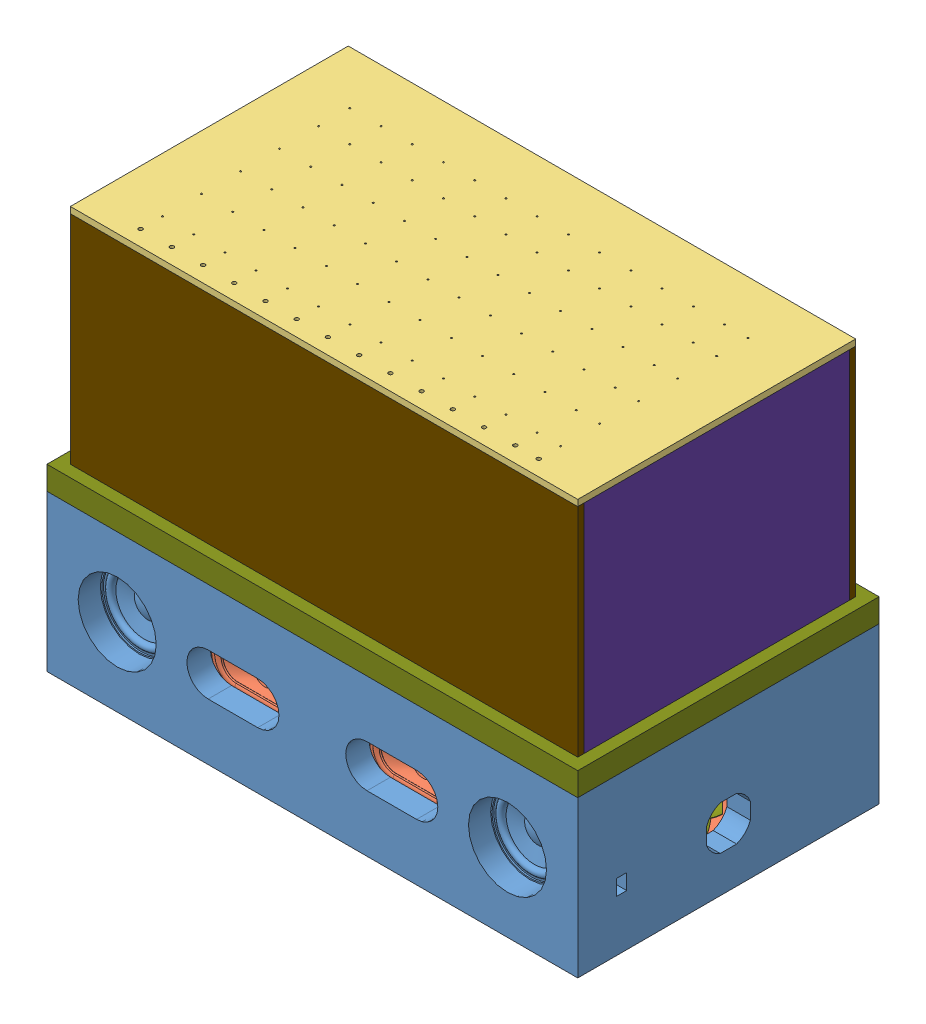
SolidWorks assembly Assem, configuration Default. Lengths in mm.
Overall size (680 515.98 386).
80 component instances, 21 part files, 41 mates.
Components (placement in the parent):
- wooden-base-1: wooden-base [Default] at (295.2164 -47.125 168.8479) size (680 200 386)
- CPU fan-1: CPU fan [Default] at (242.982 19.8629 -67.9288) x (0 -1 0) z (0 0 1) size (86 25 86)
  - Body-1: Body [Default] at (21.396 39.7345 75.157) size (86 25 86)
  - instrument ball bearing_68_am_AFBMA 12.1.4.1 - 0030-8 - Full,DE,NC,Full_68-1: instrument ball bearing_68_am_AFBMA 12.1.4.1 - 0030-8 - Full,DE,NC,Full_68 [Default] at (21.396 39.7345 75.157) x (0 -1 0) z (0 0 1) size (3.01 8 8)
  - Armature-1: Armature [Default] at (-9.8078 18.0489 67.4398) x (0.619703 0 -0.784836) z (0.784836 0 0.619703) size (38.16 6 38.16)
    - Core sub assy-1: Core sub assy [Default] at (-9.1559 6.3072 21.9798) x (0.707107 0 -0.707107) z (0.707107 0 0.707107) size (26.98 5 26.98)
    - Coil-1: Coil [Default] at (13.1895 20.6856 34.4798) x (0.999848 0 0.017452) z (-0.017452 0 0.999848) size (5 6 0.5)
    - Coil-2: Coil [Default] at (13.1807 20.6856 34.9797) x (0.999848 0 0.017452) z (-0.017452 0 0.999848) size (5 6 0.5)
    - Coil-3: Coil [Default] at (13.172 20.6856 35.4797) x (0.999848 0 0.017452) z (-0.017452 0 0.999848) size (5 6 0.5)
    - Coil-4: Coil [Default] at (13.1633 20.6856 35.9796) x (0.999848 0 0.017452) z (-0.017452 0 0.999848) size (5 6 0.5)
    - Coil-5: Coil [Default] at (13.1546 20.6856 36.4795) x (0.999848 0 0.017452) z (-0.017452 0 0.999848) size (5 6 0.5)
    - Coil-6: Coil [Default] at (13.1458 20.6856 36.9794) x (0.999848 0 0.017452) z (-0.017452 0 0.999848) size (5 6 0.5)
    - Coil-7: Coil [Default] at (13.1371 20.6856 37.4794) x (0.999848 0 0.017452) z (-0.017452 0 0.999848) size (5 6 0.5)
    - Coil-8: Coil [Default] at (13.1284 20.6856 37.9793) x (0.999848 0 0.017452) z (-0.017452 0 0.999848) size (5 6 0.5)
    - Coil-9: Coil [Default] at (13.1197 20.6856 38.4792) x (0.999848 0 0.017452) z (-0.017452 0 0.999848) size (5 6 0.5)
    - Coil-10: Coil [Default] at (13.1109 20.6856 38.9791) x (0.999848 0 0.017452) z (-0.017452 0 0.999848) size (5 6 0.5)
    - Coil-11: Coil [Default] at (13.1022 20.6856 39.4791) x (0.999848 0 0.017452) z (-0.017452 0 0.999848) size (5 6 0.5)
    - Coil-12: Coil [Default] at (13.0935 20.6856 39.979) x (0.999848 0 0.017452) z (-0.017452 0 0.999848) size (5 6 0.5)
    - Coil-13: Coil [Default] at (18.488 20.6856 29.3631) x (0.017452 0 -0.999848) z (0.999848 0 0.017452) size (5 6 0.5)
    - Coil-14: Coil [Default] at (13.3713 20.6856 24.0646) x (-0.999848 0 -0.017452) z (0.017452 0 -0.999848) size (5 6 0.5)
    - Coil-15: Coil [Default] at (8.0727 20.6856 29.1813) x (-0.017452 0 0.999848) z (-0.999848 0 -0.017452) size (5 6 0.5)
    - Coil-16: Coil [Default] at (18.9879 20.6856 29.3718) x (0.017452 0 -0.999848) z (0.999848 0 0.017452) size (5 6 0.5)
    - Coil-17: Coil [Default] at (13.38 20.6856 23.5647) x (-0.999848 0 -0.017452) z (0.017452 0 -0.999848) size (5 6 0.5)
    - Coil-18: Coil [Default] at (7.5728 20.6856 29.1726) x (-0.017452 0 0.999848) z (-0.999848 0 -0.017452) size (5 6 0.5)
    - Coil-19: Coil [Default] at (19.4878 20.6856 29.3805) x (0.017452 0 -0.999848) z (0.999848 0 0.017452) size (5 6 0.5)
    - Coil-20: Coil [Default] at (13.3887 20.6856 23.0647) x (-0.999848 0 -0.017452) z (0.017452 0 -0.999848) size (5 6 0.5)
    - Coil-21: Coil [Default] at (7.0729 20.6856 29.1638) x (-0.017452 0 0.999848) z (-0.999848 0 -0.017452) size (5 6 0.5)
    - Coil-22: Coil [Default] at (19.9877 20.6856 29.3893) x (0.017452 0 -0.999848) z (0.999848 0 0.017452) size (5 6 0.5)
    - Coil-23: Coil [Default] at (13.3974 20.6856 22.5648) x (-0.999848 0 -0.017452) z (0.017452 0 -0.999848) size (5 6 0.5)
    - Coil-24: Coil [Default] at (6.573 20.6856 29.1551) x (-0.017452 0 0.999848) z (-0.999848 0 -0.017452) size (5 6 0.5)
    - Coil-25: Coil [Default] at (20.4877 20.6856 29.398) x (0.017452 0 -0.999848) z (0.999848 0 0.017452) size (5 6 0.5)
    - Coil-26: Coil [Default] at (13.4062 20.6856 22.0649) x (-0.999848 0 -0.017452) z (0.017452 0 -0.999848) size (5 6 0.5)
    - Coil-27: Coil [Default] at (6.073 20.6856 29.1464) x (-0.017452 0 0.999848) z (-0.999848 0 -0.017452) size (5 6 0.5)
    - Coil-28: Coil [Default] at (20.9876 20.6856 29.4067) x (0.017452 0 -0.999848) z (0.999848 0 0.017452) size (5 6 0.5)
    - Coil-29: Coil [Default] at (13.4149 20.6856 21.565) x (-0.999848 0 -0.017452) z (0.017452 0 -0.999848) size (5 6 0.5)
    - Coil-30: Coil [Default] at (5.5731 20.6856 29.1377) x (-0.017452 0 0.999848) z (-0.999848 0 -0.017452) size (5 6 0.5)
    - Coil-31: Coil [Default] at (21.4875 20.6856 29.4155) x (0.017452 0 -0.999848) z (0.999848 0 0.017452) size (5 6 0.5)
    - Coil-32: Coil [Default] at (13.4236 20.6856 21.065) x (-0.999848 0 -0.017452) z (0.017452 0 -0.999848) size (5 6 0.5)
    - Coil-33: Coil [Default] at (5.0732 20.6856 29.1289) x (-0.017452 0 0.999848) z (-0.999848 0 -0.017452) size (5 6 0.5)
    - Coil-34: Coil [Default] at (21.9874 20.6856 29.4242) x (0.017452 0 -0.999848) z (0.999848 0 0.017452) size (5 6 0.5)
    - Coil-35: Coil [Default] at (13.4323 20.6856 20.5651) x (-0.999848 0 -0.017452) z (0.017452 0 -0.999848) size (5 6 0.5)
    - Coil-36: Coil [Default] at (4.5733 20.6856 29.1202) x (-0.017452 0 0.999848) z (-0.999848 0 -0.017452) size (5 6 0.5)
    - Coil-37: Coil [Default] at (22.4874 20.6856 29.4329) x (0.017452 0 -0.999848) z (0.999848 0 0.017452) size (5 6 0.5)
    - Coil-38: Coil [Default] at (13.4411 20.6856 20.0652) x (-0.999848 0 -0.017452) z (0.017452 0 -0.999848) size (5 6 0.5)
    - Coil-39: Coil [Default] at (4.0734 20.6856 29.1115) x (-0.017452 0 0.999848) z (-0.999848 0 -0.017452) size (5 6 0.5)
    - Coil-40: Coil [Default] at (22.9873 20.6856 29.4416) x (0.017452 0 -0.999848) z (0.999848 0 0.017452) size (5 6 0.5)
    - Coil-41: Coil [Default] at (13.4498 20.6856 19.5653) x (-0.999848 0 -0.017452) z (0.017452 0 -0.999848) size (5 6 0.5)
    - Coil-42: Coil [Default] at (3.5734 20.6856 29.1028) x (-0.017452 0 0.999848) z (-0.999848 0 -0.017452) size (5 6 0.5)
    - Coil-43: Coil [Default] at (23.4872 20.6856 29.4504) x (0.017452 0 -0.999848) z (0.999848 0 0.017452) size (5 6 0.5)
    - Coil-44: Coil [Default] at (13.4585 20.6856 19.0653) x (-0.999848 0 -0.017452) z (0.017452 0 -0.999848) size (5 6 0.5)
    - Coil-45: Coil [Default] at (3.0735 20.6856 29.094) x (-0.017452 0 0.999848) z (-0.999848 0 -0.017452) size (5 6 0.5)
    - Coil-46: Coil [Default] at (23.9871 20.6856 29.4591) x (0.017452 0 -0.999848) z (0.999848 0 0.017452) size (5 6 0.5)
    - Coil-47: Coil [Default] at (13.4672 20.6856 18.5654) x (-0.999848 0 -0.017452) z (0.017452 0 -0.999848) size (5 6 0.5)
    - Coil-48: Coil [Default] at (2.5736 20.6856 29.0853) x (-0.017452 0 0.999848) z (-0.999848 0 -0.017452) size (5 6 0.5)
  - instrument ball bearing_68_am_AFBMA 12.1.4.1 - 0030-8 - Full,DE,NC,Full_68-2: instrument ball bearing_68_am_AFBMA 12.1.4.1 - 0030-8 - Full,DE,NC,Full_68 [Default] at (21.396 36.7345 75.157) x (0 -1 0) z (-0.1633 0 0.986576) size (3.01 8 8)
  - Spacer-1: Spacer [Default] at (21.396 31.2345 75.157) x (0.798381 0 0.602152) z (-0.602152 0 0.798381) size (10.26 5 10.59)
  - Propeller-1: Propeller [Default] at (21.396 39.2345 75.157) x (0.99918 0 -0.040496) z (0.040496 0 0.99918) size (80 13.5 80)
  - Magnet-1: Magnet [Default] at (21.396 35.2345 75.157) x (0.999935 0 -0.011416) z (0.011416 0 0.999935) size (16.96 7 16.47)
  - Magnet-2: Magnet [Default] at (21.396 35.2345 75.157) x (-0.011416 0 -0.999935) z (0.999935 0 -0.011416) size (16.96 7 16.47)
  - Magnet-3: Magnet [Default] at (21.396 35.2345 75.157) x (-0.999935 0 0.011416) z (-0.011416 0 -0.999935) size (16.96 7 16.47)
  - Magnet-4: Magnet [Default] at (21.396 35.2345 75.157) x (0.011416 0 0.999935) z (-0.999935 0 0.011416) size (16.96 7 16.47)
  - Ring-1: Ring [Default] at (21.396 34.7343 75.157) size (3.5 0.5 3.5)
  - pan cross head_am_B18.6.7M - M2 x 0.4 x 13 Type I Cross Recessed PHMS --13S-1: pan cross head_am_B18.6.7M - M2 x 0.4 x 13 Type I Cross Recessed PHMS --13S [Default] at (22.0093 27.6345 80.3737) x (0 1 0) z (0 0 1) size (14.64 4 4.03)
  - Electric board-1: Electric board [Default] at (21.396 30.2345 75.157) x (-1 0 0) z (0 0 -1) size (31 1 31)
  - pan cross head_am_B18.6.7M - M2 x 0.4 x 13 Type I Cross Recessed PHMS --13S-2: pan cross head_am_B18.6.7M - M2 x 0.4 x 13 Type I Cross Recessed PHMS --13S [Default] at (20.7827 28.6345 69.9403) x (0 1 0) z (-0.079753 0 0.996815) size (14.64 4 4.03)
  - pan cross head_am_B18.6.7M - M2 x 0.4 x 13 Type I Cross Recessed PHMS --13S-3: pan cross head_am_B18.6.7M - M2 x 0.4 x 13 Type I Cross Recessed PHMS --13S [Default] at (22.0093 27.6345 80.3737) x (0 1 0) z (-0.079753 0 0.996815) size (14.64 4 4.03)
- stepper-holder-3: stepper-holder [Default] at (-54.2074 2.958 -99.1521) x (-1 0 0) z (0 -1 0) size (55 58 60)
- nema17-2: nema17 [Défaut] at (-26.7074 37.458 -105.1521) x (1 0 0) z (0 0 -1) size (42 42 71)
- polegon-1: polegon [Default] at (-31.5354 -62.125 -111.5201) x (1 0 0) z (0 -1 0) size (310.75 10 150)
- stepper-arm-1: stepper-arm [Default] at (-26.7074 37.458 -81.1521) x (-0.101401 -0.994846 0) z (0.994846 -0.101401 0) size (58.5 11 20)
- base-cover-1: base-cover [Default] at (325.2164 122.875 198.8479) size (680 30 386)
- acrylic2-2: acrylic2 [Default] at (-338.9836 285.8513 5.0479) x (0 1 0) z (0 0 -1) size (290 8 340)
- acrylic1-1: acrylic1 [Default] at (-14.7836 285.8513 -172.1521) x (-1 0 0) z (0 1 0) size (650 8 290)
- acrylic2-3: acrylic2 [Default] at (302.2164 285.8513 5.8479) x (0 1 0) z (0 0 -1) size (290 8 340)
- speaker-1: speaker [Default] at (-264.7841 22.9176 160.4393) x (0.999927 0.01208 0) z (0 0 1) size (104 104 56.28)
- speaker-2: speaker [Default] at (235.2138 22.9176 160.4393) x (0.998064 0.062202 0) z (0 0 1) size (104 104 56.28)
- speaker2-1: speaker2 [Default] at (-116.5226 18.7093 155.665) x (0 -1 0) z (1 0 0) size (67.43 39.85 122.6)
- speaker2-2: speaker2 [Default] at (86.0177 18.7093 155.665) x (0 -1 0) z (1 0 0) size (67.43 39.85 122.6)
- acrylic1-3: acrylic1 [Default] at (-14.7836 285.8513 183.8479) x (1 0 0) z (0 1 0) size (650 8 290)
- top-acrylic-1: top-acrylic [Default] at (310.2164 438.8513 -172.1521) x (1 0 0) z (0 0 -1) size (650 8 356)
Mates (geometry in assembly coordinates):
- Parallel2: parallel anti-aligned: plane of wooden-base-1 through (295.2164 -47.125 168.8479) normal (0 1 0); plane of stepper-holder-3 through (-54.2074 2.958 -105.1521) normal (0 -1 0)
- Parallel3: parallel anti-aligned: plane of wooden-base-1 through (295.2164 122.875 -157.1521) normal (0 0 1); plane of stepper-holder-3 through (-54.2074 2.958 -157.1521) normal (0 0 -1)
- Coincident14: coincident anti-aligned: plane of stepper-holder-3 through (-44.2074 52.958 -105.1521) normal (0 0 -1); plane of nema17-2 through (-26.7074 37.458 -105.1521) normal (0 0 1)
- Concentric2: concentric anti-aligned: circle of stepper-holder-3; circle of nema17-2
- Concentric4: concentric aligned: cylinder of stepper-holder-3 through (-26.7074 37.458 -60.1521) axis (0 0 -1) radius 11.15; cylinder of nema17-2 through (-26.7074 37.458 -81.1521) axis (0 0 -1) radius 2.5
- Coincident17: coincident anti-aligned: plane of wooden-base-1 through (295.2164 122.875 -157.1521) normal (0 0 1); plane of stepper-holder-3 through (-54.2074 2.958 -157.1521) normal (0 0 -1)
- Coincident18: coincident anti-aligned: plane of wooden-base-1 through (295.2164 122.875 168.8479) normal (-1 0 0); plane of CPU fan-1/Body-1 through (295.2164 -1.5331 7.2282) normal (1 0 0)
- Coincident19: coincident anti-aligned: plane of wooden-base-1 through (295.2164 2.958 168.8479) normal (0 1 0); plane of stepper-holder-3 through (-54.2074 2.958 -105.1521) normal (0 -1 0)
- Coincident20: coincident aligned: line of wooden-base-1 through (-54.2074 2.958 -157.1521) axis (0 0 1); line of stepper-holder-3 through (-54.2074 2.958 -157.1521) axis (0 0 1)
- Parallel4: parallel anti-aligned: plane of wooden-base-1 through (295.2164 -47.125 168.8479) normal (0 1 0); plane of polegon-1 through (-185.9673 -47.125 -424.2307) normal (0 -1 0)
- Coincident21: coincident anti-aligned: plane of wooden-base-1 through (295.2164 -47.125 168.8479) normal (0 1 0); plane of polegon-1 through (-185.9673 -47.125 -424.2307) normal (0 -1 0)
- Coincident24: coincident anti-aligned: plane of wooden-base-1 through (295.2164 2.958 -111.5201) normal (0 0 1); plane of polegon-1 through (-31.5354 -62.125 -111.5201) normal (0 0 -1)
- Concentric7: concentric aligned: cylinder of wooden-base-1 through (-158.8115 -77.125 -106.4225) axis (0 1 0) radius 2.94; cylinder of polegon-1 through (-158.8115 -77.125 -106.4225) axis (0 1 0) radius 2.94
- Concentric8: concentric anti-aligned: cylinder of nema17-2 through (-26.7074 37.458 -81.1521) axis (0 0 -1) radius 2.5; cylinder of stepper-arm-1 through (-26.7074 37.458 -92.1521) axis (0 0 1) radius 2.5
- Coincident25: coincident aligned: plane of nema17-2 through (-26.7074 37.458 -81.1521) normal (0 0 1); plane of stepper-arm-1 through (-26.7074 37.458 -81.1521) normal (0 0 1)
- Coincident36: coincident anti-aligned: plane of base-cover-1 through (-330.9836 140.8513 -163.3521) normal (-1 0 0); plane of acrylic2-2 through (-330.9836 285.8513 5.0479) normal (1 0 0)
- Coincident37: coincident anti-aligned: plane of base-cover-1 through (325.2164 140.8513 198.8479) normal (0 1 0); plane of acrylic2-2 through (-330.9836 140.8513 -164.9521) normal (0 -1 0)
- Coincident38: coincident anti-aligned: line of base-cover-1 through (-330.9836 140.8513 175.0479) axis (0 1 0); line of acrylic2-2 through (-330.9836 430.8513 175.0479) axis (0 -1 0)
- Coincident39: coincident anti-aligned: plane of base-cover-1 through (325.2164 140.8513 198.8479) normal (0 1 0); plane of acrylic1-1 through (-339.7836 140.8513 -164.1521) normal (0 -1 0)
- Coincident40: coincident anti-aligned: plane of base-cover-1 through (-339.7836 140.8513 -172.1521) normal (1 0 0); plane of acrylic1-1 through (-339.7836 430.8513 -164.1521) normal (-1 0 0)
- Coincident45: coincident anti-aligned: plane of acrylic1-1 through (-14.7836 285.8513 -164.1521) normal (0 0 1); plane of acrylic2-3 through (310.2164 430.8513 -164.1521) normal (0 0 -1)
- Coincident49: coincident anti-aligned: plane of wooden-base-1 through (295.2164 122.875 168.8479) normal (0 0 -1); plane of speaker-1 through (-264.7836 22.875 168.8479) normal (0 0 1)
- Concentric10: concentric aligned: circle of wooden-base-1; circle of speaker-1
- Coincident50: coincident anti-aligned: plane of wooden-base-1 through (295.2164 122.875 168.8479) normal (0 0 -1); plane of speaker-2 through (235.2164 22.875 168.8479) normal (0 0 1)
- Concentric11: concentric aligned: circle of wooden-base-1; circle of speaker-2
- Coincident51: coincident anti-aligned: plane of wooden-base-1 through (295.2164 122.875 168.8479) normal (0 0 -1); plane of speaker2-1 through (-173.0093 47.8263 168.8479) normal (0 0 1)
- Parallel5: parallel anti-aligned: line of wooden-base-1 through (-324.7836 122.875 168.8479) axis (1 0 0); line of speaker2-1 through (-59.6067 -15.0049 156.5881) axis (-1 0 0)
- Coincident53: coincident aligned: line of wooden-base-1 through (-148.2836 50.125 168.8479) axis (1 0 0); line of speaker2-1 through (-143.8924 50.125 168.8479) axis (1 0 0)
- Coincident54: coincident anti-aligned: plane of wooden-base-1 through (295.2164 122.875 168.8479) normal (0 0 -1); plane of speaker2-2 through (29.5311 47.8263 168.8479) normal (0 0 1)
- Coincident55: coincident aligned: line of wooden-base-1 through (55.2164 50.125 168.8479) axis (1 0 0); line of speaker2-2 through (58.6479 50.125 168.8479) axis (1 0 0)
- Coincident61: coincident anti-aligned: plane of wooden-base-1 through (295.2164 122.875 168.8479) normal (0 1 0); plane of base-cover-1 through (325.2164 122.875 198.8479) normal (0 -1 0)
- Coincident64: coincident aligned: plane of wooden-base-1 through (-354.7836 122.875 198.8479) normal (0 0 1); plane of base-cover-1 through (325.2164 152.875 198.8479) normal (0 0 1)
- Coincident65: coincident aligned: plane of wooden-base-1 through (-354.7836 122.875 -187.1521) normal (-1 0 0); plane of base-cover-1 through (-354.7836 152.875 198.8479) normal (-1 0 0)
- Coincident66: coincident anti-aligned: plane of base-cover-1 through (325.2164 140.8513 198.8479) normal (0 1 0); plane of acrylic2-3 through (310.2164 140.8513 -164.1521) normal (0 -1 0)
- Coincident67: coincident anti-aligned: plane of acrylic1-1 through (-14.7836 285.8513 -164.1521) normal (0 0 1); plane of acrylic2-3 through (310.2164 430.8513 -164.1521) normal (0 0 -1)
- Coincident68: coincident anti-aligned: plane of base-cover-1 through (310.2164 140.8513 -172.1521) normal (-1 0 0); plane of acrylic2-3 through (310.2164 285.8513 5.8479) normal (1 0 0)
- Coincident69: coincident anti-aligned: plane of base-cover-1 through (-339.7836 140.8513 183.8479) normal (0 0 -1); plane of acrylic1-3 through (-14.7836 285.8513 183.8479) normal (0 0 1)
- Coincident70: coincident aligned: line of acrylic2-3 through (310.2164 430.8513 175.8479) axis (0 -1 0); line of acrylic1-3 through (310.2164 430.8513 175.8479) axis (0 -1 0)
- Coincident71: coincident anti-aligned: plane of base-cover-1 through (325.2164 140.8513 198.8479) normal (0 1 0); plane of acrylic1-3 through (310.2164 140.8513 175.8479) normal (0 -1 0)
- Coincident72: coincident aligned: line of acrylic2-3 through (310.2164 430.8513 -164.1521) axis (0 0 1); line of top-acrylic-1 through (310.2164 430.8513 -172.1521) axis (0 0 1)
- Coincident74: coincident anti-aligned: line of acrylic1-1 through (310.2164 430.8513 -172.1521) axis (-1 0 0); line of top-acrylic-1 through (-339.7836 430.8513 -172.1521) axis (1 0 0)
